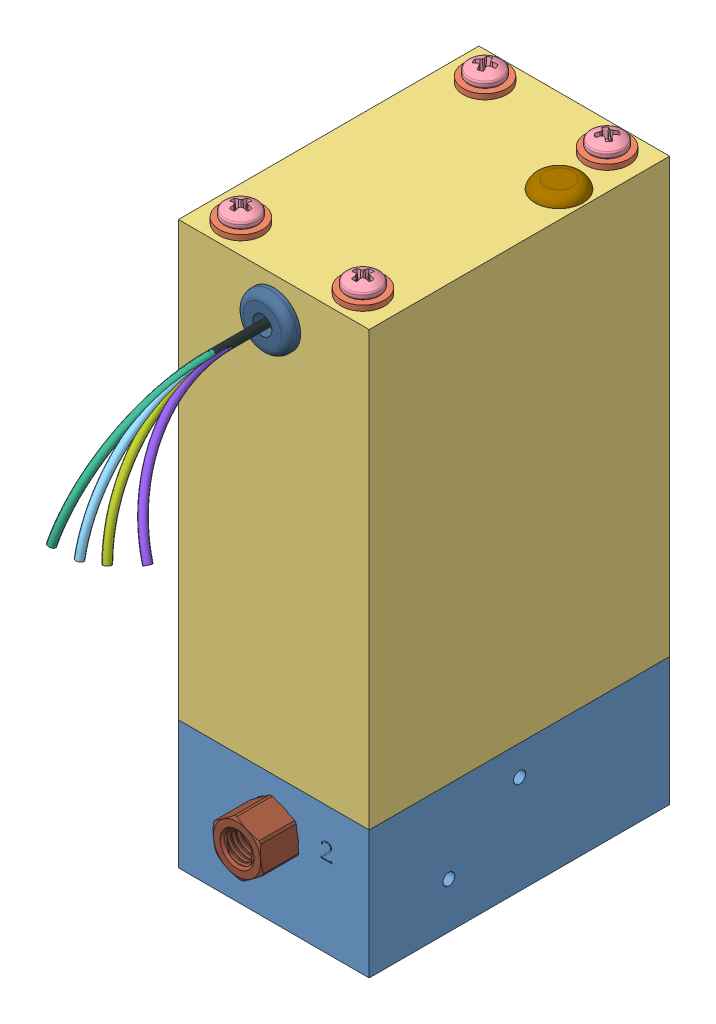
SolidWorks assembly LFR Short Housing, configuration Default. Lengths in mm.
Overall size (31.75 96.79 89.85).
19 component instances, 11 part files, 33 mates.
Components (placement in the parent):
- KPI101107-EVT-CA-1: KPI101107-EVT-CA [Default] at (15.8814 -9.3398 -42.6788) size (31.75 21.34 50.01)
- 90295A060-1: 90295A060 [Default] at (41.9164 85.0212 2.6602) x (0.552704 0 -0.833378) z (0 -1 0) size (7.24 7.24 0.89)
- 90295A060-2: 90295A060 [Default] at (41.9164 85.0212 -37.9798) x (1 0 0) z (0 -1 0) size (7.24 7.24 0.89)
- 90295A060-3: 90295A060 [Default] at (21.5964 85.0212 2.6602) x (1 0 0) z (0 -1 0) size (7.24 7.24 0.89)
- 90295A060-4: 90295A060 [Default] at (21.5964 85.0212 -37.9798) x (1 0 0) z (0 -1 0) size (7.24 7.24 0.89)
- Regulator Cover Short-1: Regulator Cover Short [Default] at (15.8814 11.9962 7.3338) x (0 0 -1) z (0 -1 0) size (50.01 31.75 72.14)
- 90272A110-1: 90272A110 [90272A110] at (41.9164 72.3212 -37.9798) x (-0.823003 0 -0.568037) z (0 1 0) size (5.56 5.56 14.8)
- 90272A110-2: 90272A110 [90272A110] at (21.5964 72.3212 2.6602) x (1 0 0) z (0 1 0) size (5.56 5.56 14.8)
- 90272A110-3: 90272A110 [90272A110] at (21.5964 72.3212 -37.9798) x (0.389111 0 0.921191) z (0 1 0) size (5.56 5.56 14.8)
- 90272A110-4: 90272A110 [90272A110] at (41.9164 72.3212 2.6602) x (1 0 0) z (0 1 0) size (5.56 5.56 14.8)
- H4BXT-10124-L8-ND-1: H4BXT-10124-L8-ND [Default] at (31.7564 77.7822 5.7647) x (-0.006108 0.999981 0) z (0.999981 0.006108 0) size (19.21 34.65 1.27)
- H4BXT-10124-B8-ND-1: H4BXT-10124-B8-ND [Default] at (31.7564 77.7822 6.4032) x (0.21197 0.977276 0) z (0.977276 -0.21197 0) size (19.21 34.65 1.27)
- H4BXT-10124-N8-ND-2: H4BXT-10124-N8-ND [Default] at (31.7564 77.7822 4.4556) x (-0.185156 0.982709 0) z (0.982709 0.185156 0) size (19.21 34.65 1.27)
- H4BXT-10124-W8-ND-2: H4BXT-10124-W8-ND [Default] at (31.7564 77.7822 2.9944) x (-0.471482 0.881876 0) z (0.881876 0.471482 0) size (19.21 34.65 1.27)
- 85985K12-1: 85985K12 [Default] at (43.1864 77.6171 -28.7088) x (1 0 0) z (0 1 0) size (7.96 7.96 7.99)
- 9600K17-2: 9600K17 [Default] at (31.7564 77.7822 9.2388) x (1 0 0) z (0 1 0) size (8.92 5.33 8.92)
- 5454K880-1: 5454K880 [5454K88] at (31.7564 4.3762 7.1052) x (0.994349 0.106157 0) z (0.106157 -0.994349 0) size (7.92 23.8 8.91)
- 5454K880-2: 5454K880 [5454K88] at (31.7564 -4.4122 -42.4502) x (-0.959172 -0.282824 0) z (0.282824 -0.959172 0) size (7.92 23.8 8.91)
- 5454K880-3: 5454K880 [5454K88] at (31.7564 4.3762 -42.4502) x (-0.959172 -0.282824 0) z (0.282824 -0.959172 0) size (7.92 23.8 8.91)
Mates (geometry in assembly coordinates):
- Concentric1: concentric aligned: cylinder of 5454K880-1 through (31.7564 4.3762 -6.3822) axis (0 0 1) radius 3.175; cylinder of KPI101107-EVT-CA-1 through (31.7564 4.3762 -6.3822) axis (0 0 1) radius 4.1021
- Coincident1: coincident anti-aligned: plane of KPI101107-EVT-CA-1 through (31.7564 4.3762 -6.3822) normal (0 0 1); plane of 5454K880-1 through (31.7564 4.3762 -6.3822) normal (0 0 -1)
- Coincident2: coincident anti-aligned: plane of KPI101107-EVT-CA-1 through (15.8814 11.9962 7.3338) normal (0 1 0); plane of Regulator Cover Short-1 through (47.6314 11.9962 7.3338) normal (0 -1 0)
- Coincident3: coincident aligned: plane of Regulator Cover Short-1 through (15.8814 84.1322 7.3338) normal (0 0 1); plane of KPI101107-EVT-CA-1 through (15.8814 11.9962 7.3338) normal (0 0 1)
- Coincident4: coincident aligned: plane of KPI101107-EVT-CA-1 through (15.8814 -9.3398 7.3338) normal (-1 0 0); plane of Regulator Cover Short-1 through (15.8814 84.1322 7.3338) normal (-1 0 0)
- Concentric3: concentric aligned: cylinder of 5454K880-3 through (31.7564 4.3762 -28.9628) axis (0 0 -1) radius 3.175; cylinder of KPI101107-EVT-CA-1 through (31.7564 4.3762 -28.9628) axis (0 0 -1) radius 4.1021
- Concentric4: concentric aligned: cylinder of KPI101107-EVT-CA-1 through (31.7564 -4.4122 -28.9628) axis (0 0 -1) radius 4.1021; cylinder of 5454K880-2 through (31.7564 -4.4122 -28.9628) axis (0 0 -1) radius 3.175
- Coincident5: coincident anti-aligned: plane of KPI101107-EVT-CA-1 through (31.7564 4.3762 -28.9628) normal (0 0 -1); plane of 5454K880-3 through (31.7564 4.3762 -28.9628) normal (0 0 1)
- Coincident6: coincident anti-aligned: plane of KPI101107-EVT-CA-1 through (31.7564 -4.4122 -28.9628) normal (0 0 -1); plane of 5454K880-2 through (31.7564 -4.4122 -28.9628) normal (0 0 1)
- Concentric5: concentric anti-aligned: cylinder of Regulator Cover Short-1 through (43.1864 81.5922 -28.7088) axis (0 1 0) radius 3.175; cylinder of 85985K12-1 through (43.1864 84.1322 -28.7088) axis (0 -1 0) radius 3.0734
- Coincident7: coincident anti-aligned: plane of Regulator Cover Short-1 through (47.6314 84.1322 7.3338) normal (0 1 0); plane of 85985K12-1 through (43.1864 84.1322 -28.7088) normal (0 -1 0)
- Concentric6: concentric aligned: cylinder of 90295A060-1 through (41.9164 84.1322 2.6602) axis (0 1 0) radius 1.651; cylinder of Regulator Cover Short-1 through (41.9164 11.9952 2.6602) axis (0 1 0) radius 1.5875
- Concentric7: concentric aligned: cylinder of 90295A060-3 through (21.5964 84.1322 2.6602) axis (0 1 0) radius 1.651; cylinder of Regulator Cover Short-1 through (21.5964 11.9952 2.6602) axis (0 1 0) radius 1.5875
- Concentric8: concentric aligned: cylinder of 90295A060-2 through (41.9164 84.1322 -37.9798) axis (0 1 0) radius 1.651; cylinder of Regulator Cover Short-1 through (41.9164 11.9952 -37.9798) axis (0 1 0) radius 1.5875
- Concentric9: concentric aligned: cylinder of 90295A060-4 through (21.5964 84.1322 -37.9798) axis (0 1 0) radius 1.651; cylinder of Regulator Cover Short-1 through (21.5964 11.9952 -37.9798) axis (0 1 0) radius 1.5875
- Coincident8: coincident anti-aligned: plane of 90295A060-2 through (41.9164 84.1322 -37.9798) normal (0 -1 0); plane of Regulator Cover Short-1 through (47.6314 84.1322 7.3338) normal (0 1 0)
- Coincident9: coincident anti-aligned: plane of 90295A060-1 through (41.9164 84.1322 2.6602) normal (0 -1 0); plane of Regulator Cover Short-1 through (47.6314 84.1322 7.3338) normal (0 1 0)
- Coincident10: coincident anti-aligned: plane of 90295A060-3 through (21.5964 84.1322 2.6602) normal (0 -1 0); plane of Regulator Cover Short-1 through (47.6314 84.1322 7.3338) normal (0 1 0)
- Coincident11: coincident anti-aligned: plane of 90295A060-4 through (21.5964 84.1322 -37.9798) normal (0 -1 0); plane of Regulator Cover Short-1 through (47.6314 84.1322 7.3338) normal (0 1 0)
- Concentric10: concentric anti-aligned: cylinder of Regulator Cover Short-1 through (41.9164 11.9952 -37.9798) axis (0 1 0) radius 1.5875; cylinder of 90272A110-1 through (41.9164 72.3212 -37.9798) axis (0 -1 0) radius 2.7813
- Concentric11: concentric anti-aligned: cylinder of Regulator Cover Short-1 through (21.5964 11.9952 -37.9798) axis (0 1 0) radius 1.5875; cylinder of 90272A110-3 through (21.5964 72.3212 -37.9798) axis (0 -1 0) radius 2.7813
- Concentric12: concentric anti-aligned: cylinder of Regulator Cover Short-1 through (41.9164 11.9952 2.6602) axis (0 1 0) radius 1.5875; cylinder of 90272A110-4 through (41.9164 72.3212 2.6602) axis (0 -1 0) radius 2.7813
- Concentric13: concentric anti-aligned: cylinder of Regulator Cover Short-1 through (21.5964 11.9952 2.6602) axis (0 1 0) radius 1.5875; cylinder of 90272A110-2 through (21.5964 72.3212 2.6602) axis (0 -1 0) radius 2.7813
- Coincident12: coincident anti-aligned: plane of 90295A060-1 through (41.9164 85.0212 2.6602) normal (0 1 0); plane of 90272A110-4 through (41.9164 85.0212 2.6602) normal (0 -1 0)
- Coincident13: coincident anti-aligned: plane of 90295A060-3 through (21.5964 85.0212 2.6602) normal (0 1 0); plane of 90272A110-2 through (21.5964 85.0212 2.6602) normal (0 -1 0)
- Coincident14: coincident anti-aligned: plane of 90295A060-2 through (41.9164 85.0212 -37.9798) normal (0 1 0); plane of 90272A110-1 through (41.9164 85.0212 -37.9798) normal (0 -1 0)
- Coincident15: coincident anti-aligned: plane of 90295A060-4 through (21.5964 85.0212 -37.9798) normal (0 1 0); plane of 90272A110-3 through (21.5964 85.0212 -37.9798) normal (0 -1 0)
- Concentric14: concentric aligned: cylinder of Regulator Cover Short-1 through (31.7564 77.7822 4.7938) axis (0 0 1) radius 1.27; cylinder of 9600K17-2 through (31.7564 77.7822 9.2388) axis (0 0 1) radius 1.905
- Coincident16: coincident anti-aligned: plane of Regulator Cover Short-1 through (15.8814 84.1322 7.3338) normal (0 0 1); plane of 9600K17-2 through (31.7564 68.2572 7.3338) normal (0 0 -1)
- Concentric15: concentric aligned: cylinder of H4BXT-10124-L8-ND-1 through (31.7564 77.7822 17.4999) axis (0 0 -1) radius 0.635; cylinder of 9600K17-2 through (31.7564 77.7822 9.2388) axis (0 0 -1) radius 1.5748
- Concentric16: concentric aligned: cylinder of H4BXT-10124-N8-ND-2 through (31.7564 77.7822 16.1909) axis (0 0 -1) radius 0.635; cylinder of 9600K17-2 through (31.7564 77.7822 9.2388) axis (0 0 -1) radius 1.5748
- Concentric17: concentric aligned: cylinder of 9600K17-2 through (31.7564 77.7822 9.2388) axis (0 0 -1) radius 1.5748; cylinder of H4BXT-10124-B8-ND-1 through (31.7564 77.7822 18.1384) axis (0 0 -1) radius 0.635
- Concentric18: concentric aligned: cylinder of 9600K17-2 through (31.7564 77.7822 9.2388) axis (0 0 -1) radius 1.5748; cylinder of H4BXT-10124-W8-ND-2 through (31.7564 77.7822 14.7296) axis (0 0 -1) radius 0.635
